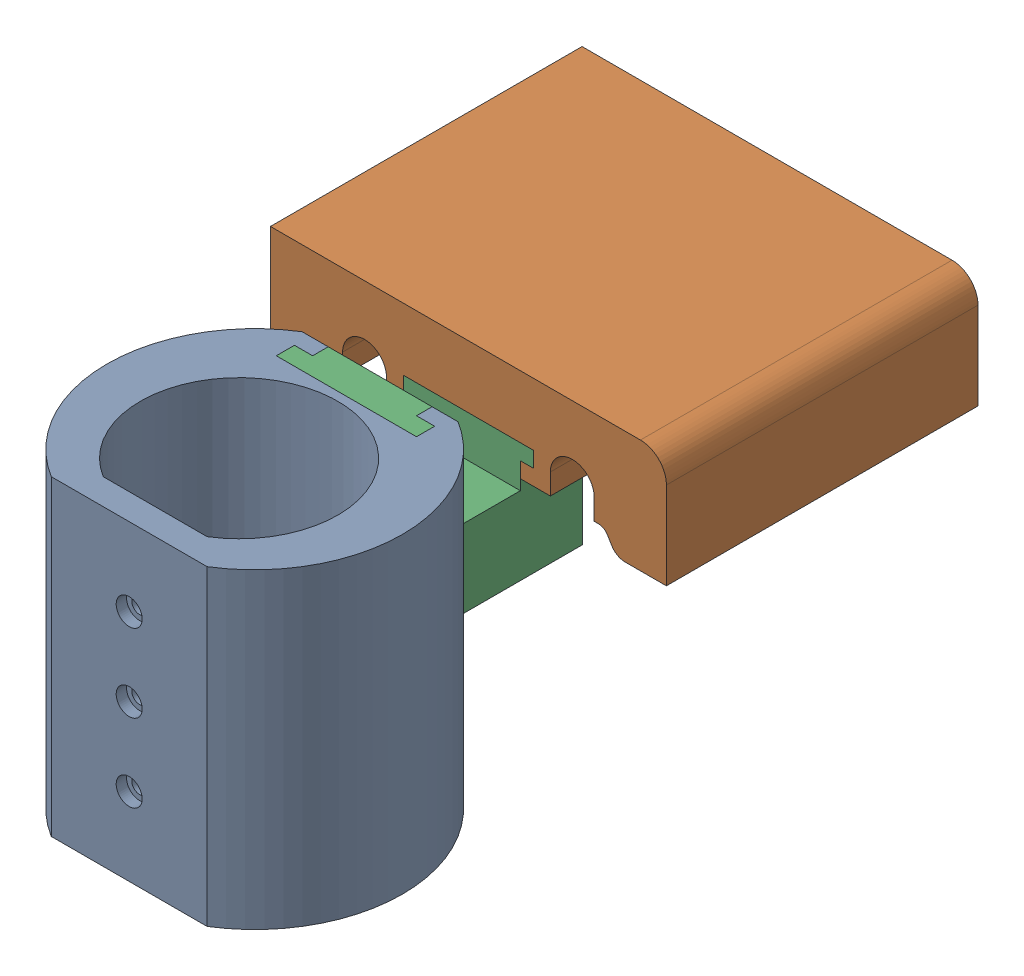
SolidWorks assembly zeiss_multipart, configuration Default. Lengths in mm.
Overall size (76.24 60 125.32).
3 component instances, 3 part files, 0 mates.
Components (placement in the parent):
- zeiss_mount_bracket_1-1: zeiss_mount_bracket_1 [Default] at origin size (56.88 60 48.32)
- zeiss_mount_bracket_2-1: zeiss_mount_bracket_2 [Default] at (0 9.5 -104.1614) x (-1 0 0) z (0 -1 0) size (76.24 60 21.82)
- zeiss_mount_bracket_3-1: zeiss_mount_bracket_3 [Default] at (0 0 -56.1614) x (0 0 -1) z (1 0 0) size (43.5 50 27)
